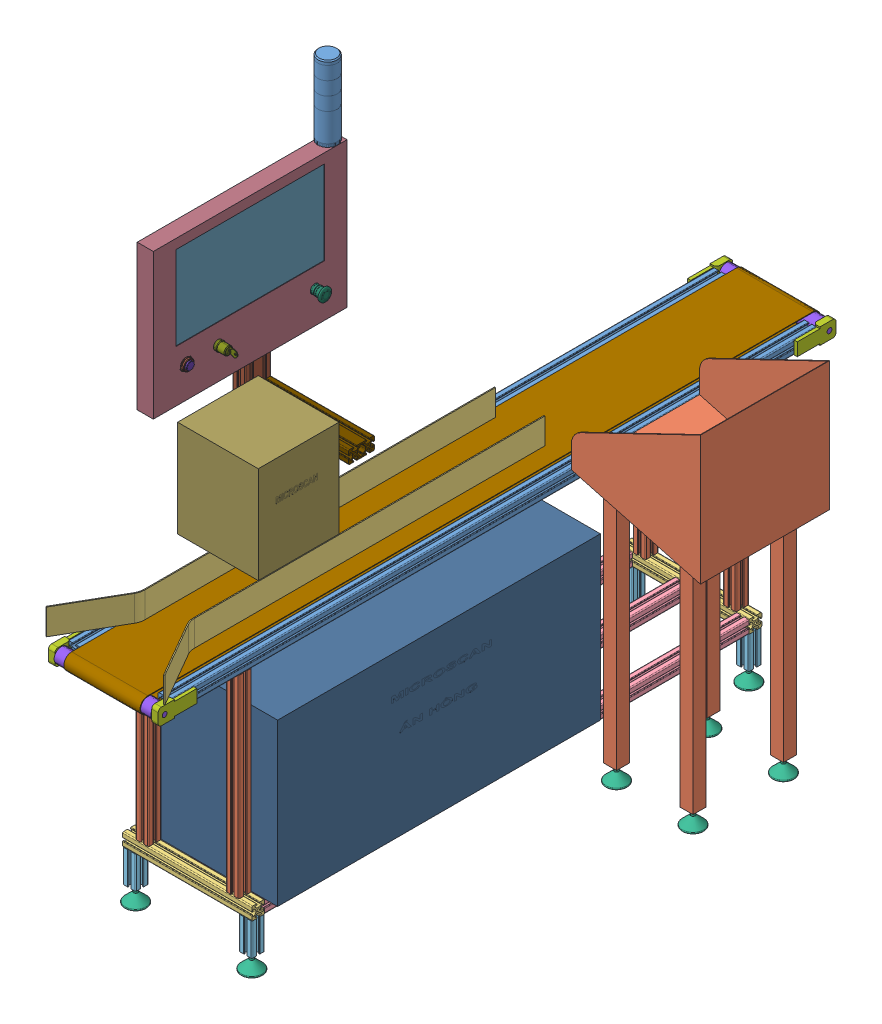
SolidWorks assembly fullcpchn, configuration Default. Lengths in mm.
Overall size (786.59 1972.4 2119.68).
64 component instances, 39 part files, 37 mates.
Components (placement in the parent):
- bang_tai-1: bang_tai [Default] at (460.0454 1554.6511 1497.0992) size (453.17 839.84 2119.68)
  - nhom 40x40x2000-1: nhom 40x40x2000 [Default] at (800.1519 1303.1912 1330.5961) size (40 40 2000)
  - nhom 40x40x600-1: nhom 40x40x600 [Default] at (800.1519 1283.1912 3100.5961) x (-1 0 0) z (0 -1 0) size (40 40 600)
  - nhom 40x40x600-2: nhom 40x40x600 [Default] at (800.1519 1283.1912 1560.5961) x (0 0 1) z (0 -1 0) size (40 40 600)
  - nhom 40x40x2000-2: nhom 40x40x2000 [Default] at (1080.1519 1303.1912 1330.5961) size (40 40 2000)
  - nhom 40x40x600-3: nhom 40x40x600 [Default] at (1080.1519 1283.1912 3100.5961) x (-1 0 0) z (0 -1 0) size (40 40 600)
  - nhom 40x40x600-4: nhom 40x40x600 [Default] at (1080.1519 1283.1912 1560.5961) x (0 0 1) z (0 -1 0) size (40 40 600)
  - nhom 40x40x400-1: nhom 40x40x400 [Default] at (740.1519 663.1912 1560.5961) x (0 0 -1) z (1 0 0) size (40 40 400)
  - nhom 40x40x400-2: nhom 40x40x400 [Default] at (740.1519 663.1912 3100.5961) x (0 0 -1) z (1 0 0) size (40 40 400)
  - nhom 40x40x1500-1: nhom 40x40x1500 [Default] at (930.1519 663.1912 1580.5961) size (40 40 1500)
  - nhom 40x40x100-1: nhom 40x40x100 [Default] at (1120.1519 643.1912 1560.5961) x (1 0 0) z (0 -1 0) size (40 40 100)
  - nhom 40x40x100-2: nhom 40x40x100 [Default] at (760.1519 643.1912 1560.5961) x (1 0 0) z (0 -1 0) size (40 40 100)
  - nhom 40x40x100-3: nhom 40x40x100 [Default] at (760.1519 643.1912 3100.5961) x (1 0 0) z (0 -1 0) size (40 40 100)
  - nhom 40x40x100-4: nhom 40x40x100 [Default] at (1120.1519 643.1912 3100.5961) x (1 0 0) z (0 -1 0) size (40 40 100)
  - bat_de-1: bat_de [Default] at (1120.1519 493.1912 3100.5961) x (0.747731 0 -0.664002) z (0.664002 0 0.747731) size (66 80 66)
  - bat_de-2: bat_de [Default] at (1120.1519 493.1912 1560.5961) x (0.747731 0 -0.664002) z (0.664002 0 0.747731) size (66 80 66)
  - bat_de-3: bat_de [Default] at (760.1519 493.1912 3100.5961) x (0.747731 0 -0.664002) z (0.664002 0 0.747731) size (66 80 66)
  - bat_de-4: bat_de [Default] at (760.1519 493.1912 1560.5961) x (0.747731 0 -0.664002) z (0.664002 0 0.747731) size (66 80 66)
  - bat truc-1: bat truc [Default] at (1110.1519 1303.1912 1330.5961) x (0 0 -1) z (-1 0 0) size (120 50 20)
  - bat truc-2: bat truc [Default] at (770.1519 1303.1912 1330.5961) x (0 0 -1) z (1 0 0) size (120 50 20)
  - bat truc-3: bat truc [Default] at (770.1519 1303.1912 3330.5961) x (0 0 1) z (1 0 0) size (120 50 20)
  - bat truc-4: bat truc [Default] at (1110.1519 1303.1912 3330.5961) x (0 0 1) z (-1 0 0) size (120 50 20)
  - truc lan-1: truc lan [Default] at (790.1519 1303.1912 3360.5961) x (0 -0.417649 -0.908609) z (1 0 0) size (45 45 340)
  - truc lan-2: truc lan [Default] at (790.1519 1303.1912 1300.5961) x (0 -0.417649 -0.908609) z (1 0 0) size (45 45 340)
  - Belt2-4^bang_tai-1: Belt2-4^bang_tai [Default] at (940.1519 1303.1912 3360.5961) x (0 0 1) z (-1 0 0) size (2109 49 236) (virtual)
  - nhom 40x40x1500-2: nhom 40x40x1500 [Default] at (1120.1519 663.1912 1580.5961) size (40 40 1500)
  - nhom 40x40x1500-3: nhom 40x40x1500 [Default] at (760.1519 663.1912 1580.5961) size (40 40 1500)
- tu dien - Sao chép-1: tu dien - Sao chép [Default] at (1440.1972 2737.8423 4077.6953) x (0 0 -1) z (0 -1 0) size (1000 400 500)
- 40x80x1000-3: 40x80x1000 [Default] at (1220.1972 3337.8423 4237.6953) x (0 0 1) z (0 -1 0) size (80 40.01 1100)
- cover camera-1: cover camera [Default] at (1405.1972 3332.3423 4402.6953) x (0 0 -1) z (0 -1 0) size (250 250 300)
- tu dien - Sao chép-2: tu dien - Sao chép [Default] at (1010.4426 3501.7124 4484.5857) x (0 0 -1) z (0 -1 0) size (600 118.01 450)
  - bat man hinh-1: bat man hinh [Default] at (221.8904 179.7546 -61.13) x (1 0 0) z (0 1 0) size (600 450 50)
  - man hinh-1: man hinh [Default] at (221.8904 208.2546 -126.13) x (1 0 0) z (0 1 0) size (500 300 20)
  - User Library-E Stop Button-1: User Library-E Stop Button [Default] at (421.8904 241.2546 63.87) size (39 70.54 39)
  - G_IC03_XX_28762V-1: G_IC03_XX_28762V [Default] at (121.8933 229.7546 64.07) x (-0.999896 0 0.014408) z (0.014408 0 0.999896) size (29.48 86.4 29.48)
  - dr30e3l-l3gzc-1: dr30e3l-l3gzc [Default] at (23.1032 185.1546 64.858) x (0.429366 0 0.903131) z (0 1 0) size (41 40.2 73.47)
    - dr30e3l-l3gzc_01-1: dr30e3l-l3gzc_01 [Default] at origin size (6.6 6.56 0.7)
    - dr30e3l-l3gzc_02-1: dr30e3l-l3gzc_02 [Default] at origin size (7.7 7.7 1.5)
    - dr30e3l-l3gzc_03-1: dr30e3l-l3gzc_03 [Default] at origin size (39 39 1.5)
    - dr30e3l-l3gzc_04-1: dr30e3l-l3gzc_04 [Default] at origin size (9.1 7.7 3)
    - dr30e3l-l3gzc_05-1: dr30e3l-l3gzc_05 [Default] at origin size (39 39 1.5)
    - dr30e3l-l3gzc_06-1: dr30e3l-l3gzc_06 [Default] at origin size (7.7 7.7 1.5)
    - dr30e3l-l3gzc_07-1: dr30e3l-l3gzc_07 [Default] at origin size (9.1 7.7 3)
    - dr30e3l-l3gzc_08-1: dr30e3l-l3gzc_08 [Default] at origin size (6.6 6.56 0.7)
    - dr30e3l-l3gzc_09-1: dr30e3l-l3gzc_09 [Default] at origin size (7.54 7.17 9.3)
    - dr30e3l-l3gzc_10-1: dr30e3l-l3gzc_10 [Default] at origin size (18.4 29 8.21)
    - dr30e3l-l3gzc_11-1: dr30e3l-l3gzc_11 [Default] at origin size (10 10.77 19.53)
    - dr30e3l-l3gzc_12-1: dr30e3l-l3gzc_12 [Default] at origin size (41 40.2 27.4)
    - dr30e3l-l3gzc_13-1: dr30e3l-l3gzc_13 [Default] at origin size (35 35 10)
    - dr30e3l-l3gzc_14-1: dr30e3l-l3gzc_14 [Default] at origin size (39 39 1.5)
    - dr30e3l-l3gzc_15-1: dr30e3l-l3gzc_15 [Default] at origin size (6.5 6.5 9.3)
    - dr30e3l-l3gzc_16-1: dr30e3l-l3gzc_16 [Default] at origin size (19.8 29.9 44.3)
    - dr30e3l-l3gzc_17-1: dr30e3l-l3gzc_17 [Default] at origin size (26.07 30 22.8)
    - dr30e3l-l3gzc_18-1: dr30e3l-l3gzc_18 [Default] at origin size (39 39 1.5)
    - dr30e3l-l3gzc_19-1: dr30e3l-l3gzc_19 [Default] at origin size (29.15 29.06 9.16)
- 40x80x320-5: 40x80x320 [Default] at (1240.1972 3252.3479 4237.6953) x (0 0 -1) z (1 0 0) size (80 40.01 320)
- User Library-p000557 light tower-1: User Library-p000557 light tower [Default] at (1210.1972 3787.8423 3992.6953) size (60 245.1 60)
- gia loai sp-1: gia loai sp [Default] at (1960.1972 2767.5568 3187.6953) size (400 1069.71 400)
- bat_de-1: bat_de [Default] at (1640.1972 2047.8423 3247.6953) x (0.747731 0 -0.664002) z (0.664002 0 0.747731) size (66 80 66)
- bat_de-2: bat_de [Default] at (1640.1972 2047.8423 3527.6953) x (0.747731 0 -0.664002) z (0.664002 0 0.747731) size (66 80 66)
- bat_de-3: bat_de [Default] at (1877.1972 2047.8423 3527.6953) x (0.989149 0 -0.146915) z (0.146915 0 0.989149) size (66 80 66)
- bat_de-4: bat_de [Default] at (1877.1972 2047.8423 3247.6953) x (0.747731 0 -0.664002) z (0.664002 0 0.747731) size (66 80 66)
- thanh dan hương-1: thanh dan hương [Default] at (1475.1972 2897.8423 3587.6953) x (0 0 -1) z (0 1 0) size (1284.81 109.3 80)
- thanh dan hương-2: thanh dan hương [Default] at (1325.1972 2977.8423 3587.6953) x (0 0 -1) z (0 -1 0) size (1284.81 109.3 80)
Mates (geometry in assembly coordinates):
- Coincident1: coincident anti-aligned: plane of bang_tai-1/nhom 40x40x1500-2 through (1563.3672 2237.8423 4577.6953) normal (0 1 0); plane of tu dien - Sao chép-1 through (1440.1972 2237.8423 4077.6953) normal (0 -1 0)
- Coincident2: coincident anti-aligned: plane of bang_tai-1/nhom 40x40x600-3 through (1534.5672 2237.8423 4577.6953) normal (0 0 -1); plane of tu dien - Sao chép-1 through (1240.1972 2237.8423 4577.6953) normal (0 0 1)
- Coincident3: coincident aligned: plane of bang_tai-1/nhom 40x40x600-1 through (1240.1972 2237.8423 4614.5253) normal (-1 0 0); plane of tu dien - Sao chép-1 through (1240.1972 2237.8423 3577.6953) normal (-1 0 0)
- Coincident10: coincident aligned: plane of bang_tai-1/nhom 40x40x1500-3 through (1200.1972 2200.824 4577.6953) normal (-1 0 0); plane of 40x80x1000-3 through (1200.1972 2237.8423 4223.3234) normal (-1 0 0)
- Coincident11: coincident anti-aligned: plane of bang_tai-1/nhom 40x40x1500-3 through (1203.3672 2237.8423 4577.6953) normal (0 1 0); plane of 40x80x1000-3 through (1238.6272 2237.8423 4252.0653) normal (0 -1 0)
- Distance2: distance = 150 mm anti-aligned: plane of cover camera-1 through (1405.1972 3032.3423 4402.6953) normal (0 -1 0); plane of bang_tai-1/Belt2-4^bang_tai-1 through (1282.1972 2882.3423 2797.6953) normal (0 1 0)
- Distance5: distance = 40 mm anti-aligned: plane of cover camera-1 through (1280.1972 3032.3423 4277.6953) normal (-1 0 0); plane of 40x80x1000-3 through (1240.1972 2237.8423 4252.0653) normal (1 0 0)
- Coincident32: coincident anti-aligned: plane of cover camera-1 through (1280.1972 3032.3423 4277.6953) normal (0 0 -1); plane of 40x80x320-5 through (1560.1972 3265.3585 4277.6953) normal (0 0 1)
- Coincident39: coincident anti-aligned: plane of 40x80x1000-3 through (1238.6272 3337.8423 4252.0653) normal (0 1 0); plane of tu dien - Sao chép-2/bat man hinh-1 through (1240.1972 3337.8423 3962.6953) normal (0 -1 0)
- Distance8: distance = 235 mm aligned: plane of tu dien - Sao chép-2/bat man hinh-1 through (1240.1972 3787.8423 3962.6953) normal (0 0 -1); plane of 40x80x1000-3 through (1233.1972 2237.8423 4197.6953) normal (0 0 -1)
- Coincident41: coincident aligned: plane of 40x80x1000-3 through (1240.1972 2237.8423 4252.0653) normal (1 0 0); plane of tu dien - Sao chép-2/bat man hinh-1 through (1240.1972 3562.8423 4262.6953) normal (1 0 0)
- Distance9: distance = 300 mm anti-aligned: plane of bang_tai-1/nhom 40x40x600-1 through (1254.5672 2237.8423 4577.6953) normal (0 0 -1); plane of 40x80x1000-3 through (1203.3566 2237.8423 4277.6953) normal (0 0 1)
- Coincident43: coincident aligned: plane of 40x80x1000-3 through (1207.1866 2237.8423 4197.6953) normal (0 0 -1); plane of 40x80x320-5 through (1560.1972 3269.1885 4197.6953) normal (0 0 -1)
- Coincident44: coincident anti-aligned: plane of 40x80x1000-3 through (1240.1972 2237.8423 4204.4679) normal (1 0 0); plane of 40x80x320-5 through (1240.1972 3233.9179 4223.3253) normal (-1 0 0)
- Coincident45: coincident anti-aligned: plane of tu dien - Sao chép-2/bat man hinh-1 through (1240.1972 3787.8423 3962.6953) normal (0 1 0); plane of User Library-p000557 light tower-1 through (1210.1972 3787.8423 3992.6953) normal (0 -1 0)
- Tangent1: tangent aligned: plane of tu dien - Sao chép-2/bat man hinh-1 through (1240.1972 3562.8423 4262.6953) normal (1 0 0); cylinder of User Library-p000557 light tower-1 through (1210.1972 4020.2423 3992.6953) axis (0 -1 0) radius 30
- Tangent2: tangent aligned: plane of tu dien - Sao chép-2/bat man hinh-1 through (1240.1972 3787.8423 3962.6953) normal (0 0 -1); cylinder of User Library-p000557 light tower-1 through (1210.1972 4020.2423 3992.6953) axis (0 -1 0) radius 30
- Coincident46: coincident: plane of bang_tai-1/nhom 40x40x2000-2 through (1545.8272 2877.8423 4827.6953) normal (0 1 0); line of gia loai sp-1 through (1560.1972 2877.8423 3584.6953) axis (0 0 -1)
- Coincident47: coincident anti-aligned: plane of bang_tai-1/nhom 40x40x2000-2 through (1560.1972 2870.8434 4827.6953) normal (1 0 0); plane of gia loai sp-1 through (1560.1972 2874.7365 3587.6953) normal (-1 0 0)
- Distance10: distance = 150 mm anti-aligned: plane of gia loai sp-1 through (1620.1972 2097.8468 3227.6953) normal (0 0 -1); plane of bang_tai-1/nhom 40x40x600-4 through (1557.0272 2237.8423 3077.6953) normal (0 0 1)
- Concentric1: concentric aligned: cylinder of gia loai sp-1 through (1877.1972 2117.8468 3527.6953) axis (0 -1 0) radius 7.5; cylinder of bat_de-3 through (1877.1972 2127.8423 3527.6953) axis (0 -1 0) radius 6.5164
- Concentric2: concentric aligned: cylinder of gia loai sp-1 through (1640.1972 2117.8468 3527.6953) axis (0 -1 0) radius 7.5; cylinder of bat_de-2 through (1640.1972 2127.8423 3527.6953) axis (0 -1 0) radius 6.5164
- Concentric3: concentric aligned: cylinder of gia loai sp-1 through (1877.1972 2117.8468 3247.6953) axis (0 -1 0) radius 7.5; cylinder of bat_de-4 through (1877.1972 2127.8423 3247.6953) axis (0 -1 0) radius 6.5164
- Concentric4: concentric aligned: cylinder of gia loai sp-1 through (1640.1972 2117.8468 3247.6953) axis (0 -1 0) radius 7.5; cylinder of bat_de-1 through (1640.1972 2127.8423 3247.6953) axis (0 -1 0) radius 6.5164
- Coincident50: coincident aligned: plane of bat_de-1 through (1662.6291 2047.8423 3227.7752) normal (0 -1 0); plane of bat_de-2 through (1662.6291 2047.8423 3507.7752) normal (0 -1 0)
- Coincident51: coincident aligned: plane of bat_de-2 through (1662.6291 2047.8423 3507.7752) normal (0 -1 0); plane of bat_de-4 through (1899.6291 2047.8423 3227.7752) normal (0 -1 0)
- Coincident52: coincident aligned: plane of bat_de-3 through (1906.8717 2047.8423 3523.2879) normal (0 -1 0); plane of bat_de-4 through (1899.6291 2047.8423 3227.7752) normal (0 -1 0)
- Coincident53: coincident aligned: plane of bang_tai-1/bat_de-2 through (1602.6291 2047.8423 3037.7752) normal (0 -1 0); plane of bat_de-1 through (1662.6291 2047.8423 3227.7752) normal (0 -1 0)
- Parallel1: parallel aligned: plane of bang_tai-1/bat truc-4 through (1570.1972 2857.8423 4827.6953) normal (1 0 0); plane of thanh dan hương-1 through (1478.1972 2977.8423 3587.6953) normal (1 0 0)
- Parallel2: parallel aligned: plane of bang_tai-1/Belt2-4^bang_tai-1 through (1282.1972 2882.3423 2797.6953) normal (0 1 0); plane of thanh dan hương-1 through (1525.1972 2977.8423 4674.2978) normal (0 1 0)
- Distance11: distance = 20 mm anti-aligned: plane of thanh dan hương-1 through (1525.1972 2897.8423 4674.2978) normal (0 -1 0); plane of bang_tai-1/nhom 40x40x2000-2 through (1523.3672 2877.8423 4827.6953) normal (0 1 0)
- Parallel3: parallel anti-aligned: plane of thanh dan hương-1 through (1475.1972 2977.8423 4674.2978) normal (-1 0 0); plane of thanh dan hương-2 through (1325.1972 2897.8423 4674.2978) normal (1 0 0)
- Coincident58: coincident aligned: plane of thanh dan hương-1 through (1525.1972 2977.8423 4674.2978) normal (0 1 0); plane of thanh dan hương-2 through (1275.1972 2977.8423 4674.2978) normal (0 1 0)
- Coincident59: coincident aligned: plane of thanh dan hương-1 through (1475.1972 2977.8423 3587.6953) normal (0 0 -1); plane of thanh dan hương-2 through (1325.1972 2897.8423 3587.6953) normal (0 0 -1)
- Coincident60: coincident anti-aligned: plane of gia loai sp-1 through (1960.1972 2767.5568 3587.6953) normal (0 0 1); plane of thanh dan hương-1 through (1475.1972 2977.8423 3587.6953) normal (0 0 -1)
- Distance12: distance = 150 mm anti-aligned: plane of thanh dan hương-2 through (1325.1972 2897.8423 4674.2978) normal (1 0 0); plane of thanh dan hương-1 through (1475.1972 2977.8423 4674.2978) normal (-1 0 0)
- Distance13: distance = 82 mm aligned: plane of thanh dan hương-1 through (1478.1972 2977.8423 3587.6953) normal (1 0 0); plane of bang_tai-1/nhom 40x40x2000-2 through (1560.1972 2870.8434 4827.6953) normal (1 0 0)
